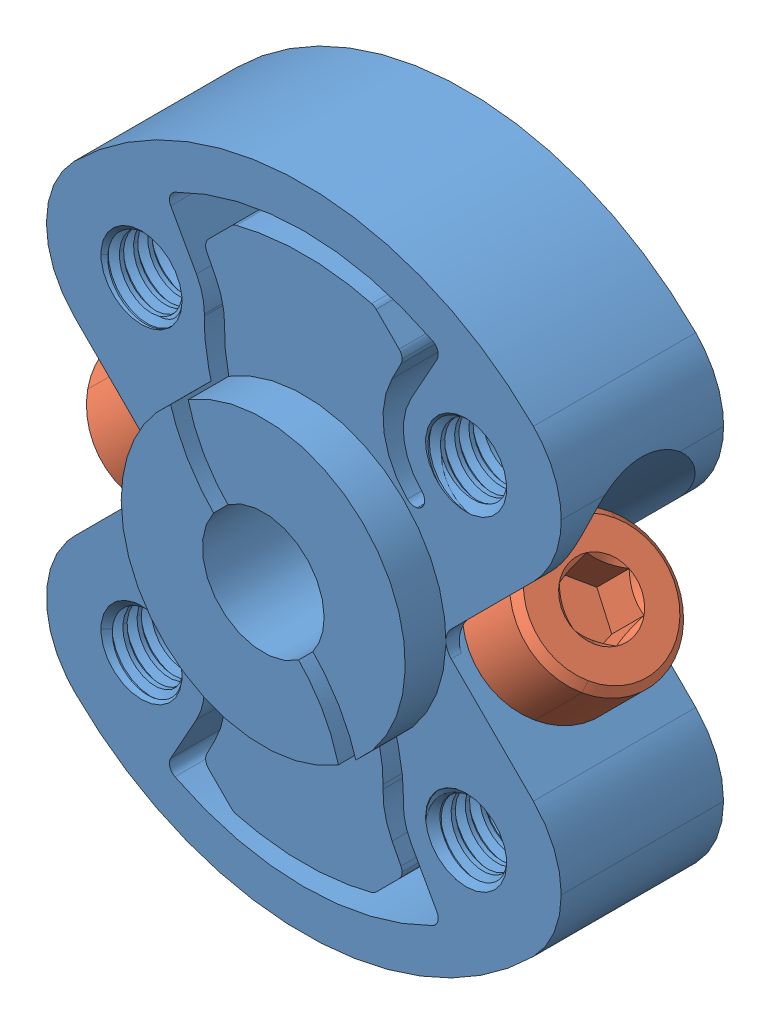
SolidWorks assembly 6mm Hub 1309-0016-0006, configuration Default. Lengths in mm.
Overall size (28.36 32 10.95).
3 component instances, 2 part files, 0 mates.
Components (placement in the parent):
- 1309-0016-0006.STEP-1: 1309-0016-0006.STEP [Default] at (-4.9736 1.2999 1.3025) size (25.38 32 10)
- 2800-0004-0014_90128A207.STEP-1: 2800-0004-0014_90128A207.STEP [Default] at (-2.9207 12.4187 1.3025) x (0.5 -0.5 -0.707107) z (0.707107 0.707107 0) size (7 7 18.01)
- 2800-0004-0014_90128A207.STEP-2: 2800-0004-0014_90128A207.STEP [Default] at (-7.0264 -9.8188 1.3025) x (-0.5 0.5 -0.707107) z (-0.707107 -0.707107 0) size (7 7 18.01)
